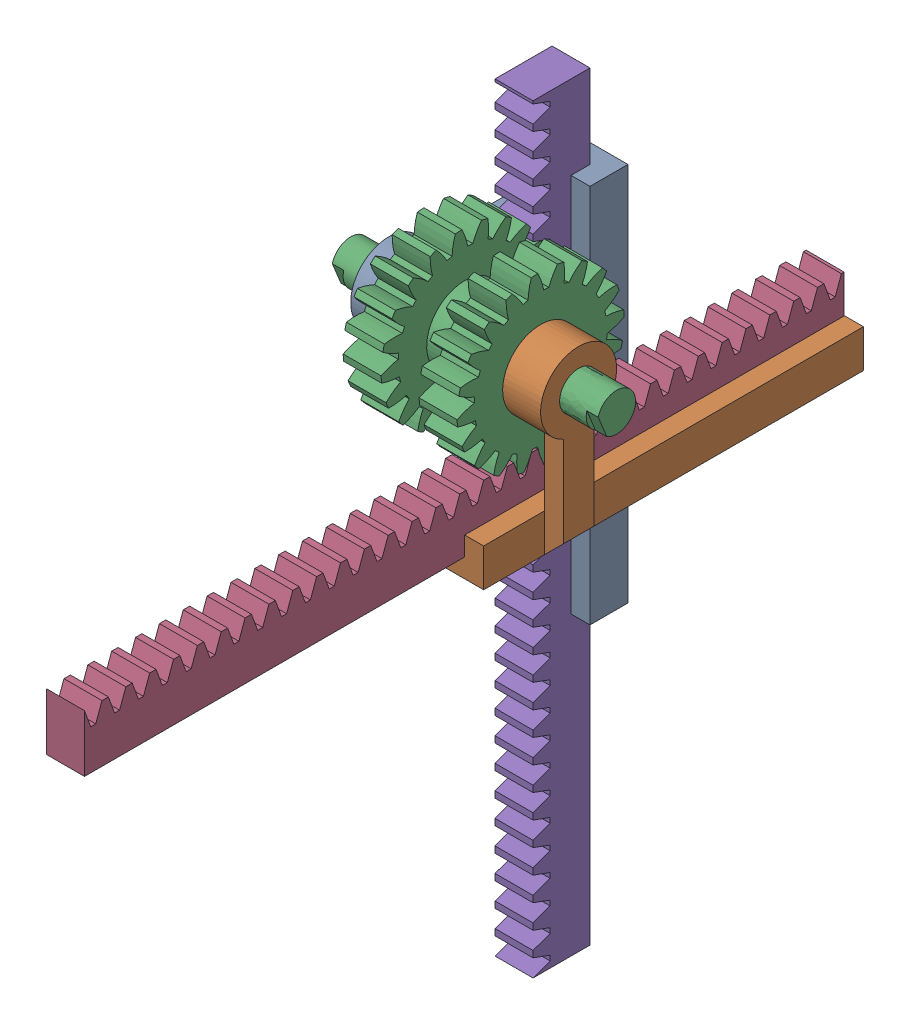
SolidWorks assembly Rack Pinion, configuration Default. Lengths in mm.
Overall size (70 200 200.09).
5 component instances, 3 part files, 12 mates.
Components (placement in the parent):
- Base2-1: Base2 [Default] at (265.5114 -167.4193 -72.2519) size (25 100 48)
- Base2-2: Base2 [Default] at (325.5114 -187.9193 -51.7519) x (-1 0 0) z (0 1 0) size (25 100 48)
- Gea20-1: Gea20 [Default] at (290.5114 -167.4193 -51.7519) x (0 -0.926247 -0.376917) z (-1 0 0) size (44 44 70)
- Rack1-1: Rack1 [Default] at (310.5114 -185.4193 68.3365) x (0 0 -1) z (0 1 0) size (200 10 15)
- Rack1-2: Rack1 [Default] at (290.5114 -325.4193 -69.7519) x (0 1 0) z (0 0 1) size (200 10 15)
Mates (geometry in assembly coordinates):
- Concentric1: concentric anti-aligned: cylinder of Base2-1 through (275.5114 -167.4193 -51.7519) axis (-1 0 0) radius 10; cylinder of Base2-2 through (315.5114 -167.4193 -51.7519) axis (1 0 0) radius 10
- Coincident1: coincident anti-aligned: plane of Base2-1 through (295.5114 -147.4193 -79.7519) normal (1 0 0); plane of Base2-2 through (295.5114 -195.4193 -31.7519) normal (-1 0 0)
- Parallel1: parallel aligned: plane of Base2-1 through (285.5114 -147.4193 -85.1091) normal (0 1 0); plane of Base2-2 through (300.5114 -195.4193 -31.7519) normal (0 1 0)
- Coincident3: coincident aligned: plane of Base2-2 through (310.5114 -159.9193 -51.7519) normal (-1 0 0); circle of Gea20-1
- Concentric2: concentric aligned: cylinder of Base2-1 through (275.5114 -167.4193 -51.7519) axis (-1 0 0) radius 10; cylinder of Gea20-1 through (280.5114 -167.4193 -51.7519) axis (-1 0 0) radius 5
- Coincident4: coincident anti-aligned: plane of Base2-2 through (310.5114 -195.4193 -31.7519) normal (-1 0 0); plane of Rack1-1 through (310.5114 -185.4193 68.3365) normal (1 0 0)
- Coincident5: coincident anti-aligned: plane of Base2-2 through (310.5114 -200.4193 -31.7519) normal (0 1 0); plane of Rack1-1 through (305.5114 -200.4193 -31.6635) normal (0 -1 0)
- Coincident6: coincident anti-aligned: plane of Base2-1 through (290.5114 -147.4193 -84.7519) normal (-1 0 0); plane of Rack1-2 through (290.5114 -325.4193 -69.7519) normal (1 0 0)
- Coincident7: coincident anti-aligned: plane of Base2-1 through (280.5114 -147.4193 -84.7519) normal (0 0 1); plane of Rack1-2 through (285.5114 -225.4193 -84.7519) normal (0 0 -1)
- RackPinionMate1: rack pinion = 40 mm: line of Rack1-2 through (290.5114 -203.1413 -74.2519) axis (0 -1 0); circle of Gea20-1
- RackPinionMate2: rack pinion = 40 mm: line of Rack1-1 through (310.5114 -189.9193 -9.9815) axis (0 0 1); circle of Gea20-1
- LimitDistance1: limit distance = 22 mm aligned: plane of Rack1-2 through (290.5114 -125.4193 -69.7519) normal (0 1 0); plane of Base2-1 through (285.5114 -147.4193 -85.1091) normal (0 1 0)
